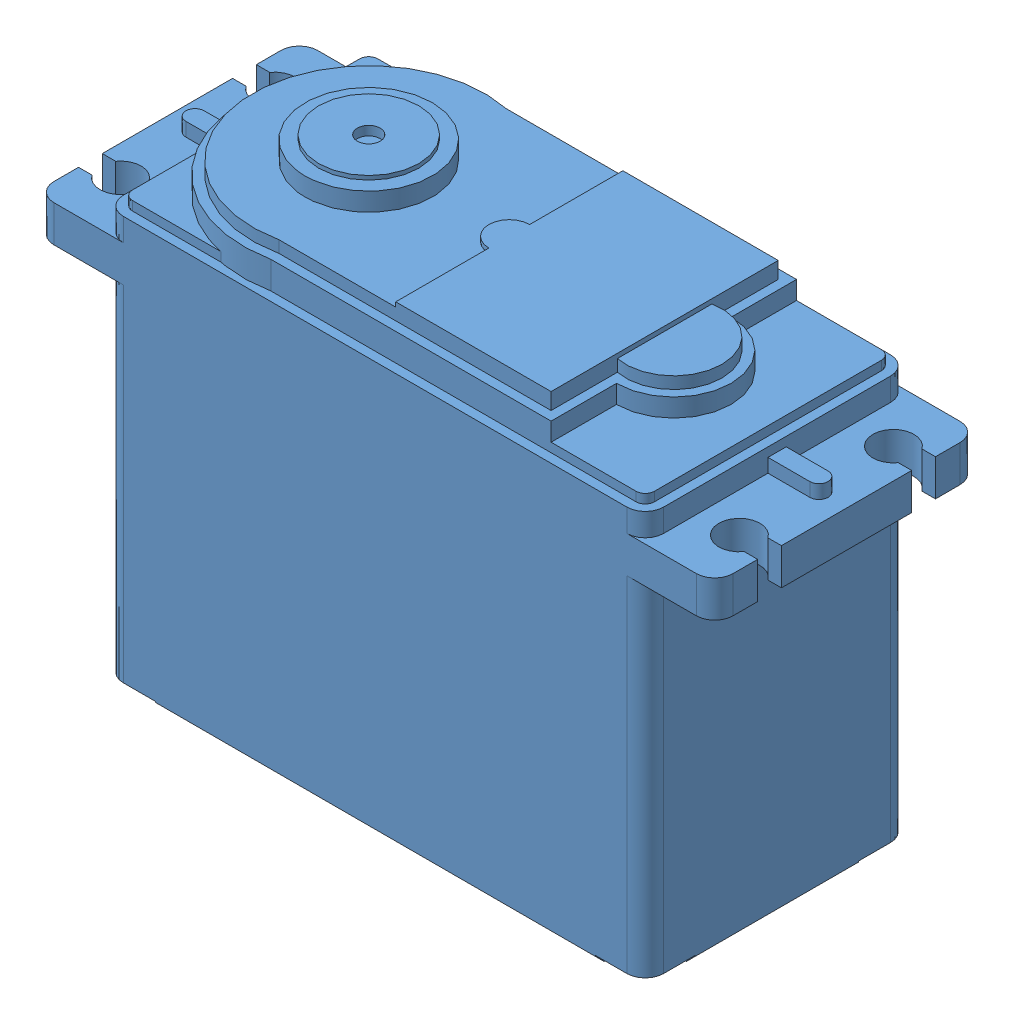
SolidWorks assembly Servo_motor, configuration Predeterminado. Lengths in mm.
Overall size (74.3 52.21 28.85).
5 component instances, 2 part files, 2 mates.
Components (placement in the parent):
- Carcasa Servo Hitec HB-755HB-1: Carcasa Servo Hitec HB-755HB [Predeterminado] at (-14.8098 -5.2866 74.3) size (74.3 52.04 28.85)
- pan cross head screw_as-1: pan cross head screw_as [AS-NZS 1427 PC- M1.6 x 5-N] at (12.2402 -28.1366 62.375) x (0 1 0) z (0 0 1) size (6.27 3.2 3.2)
- pan cross head screw_as-2: pan cross head screw_as [AS-NZS 1427 PC- M1.6 x 5-N] at (12.2402 -28.1366 86.225) x (0 1 0) z (0 0 1) size (6.27 3.2 3.2)
- pan cross head screw_as-3: pan cross head screw_as [AS-NZS 1427 PC- M1.6 x 5-N] at (-41.8598 -28.1366 86.225) x (0 1 0) z (0 0 1) size (6.27 3.2 3.2)
- pan cross head screw_as-4: pan cross head screw_as [AS-NZS 1427 PC- M1.6 x 5-N] at (-41.8598 -28.1366 62.375) x (0 1 0) z (0 0 1) size (6.27 3.2 3.2)
Mates (geometry in assembly coordinates):
- Concéntrica181: concentric aligned: cylinder of Carcasa Servo Hitec HB-755HB-1 through (12.2402 -26.8366 62.375) axis (0 -1 0) radius 0.9; cylinder of pan cross head screw_as-1 through (12.2402 -28.1366 62.375) axis (0 -1 0) radius 0.8
- Coincidente181: coincident anti-aligned: plane of Carcasa Servo Hitec HB-755HB-1 through (11.2402 -26.8366 63.375) normal (0 -1 0); plane of pan cross head screw_as-1 through (11.4402 -26.8366 62.375) normal (0 1 0)
